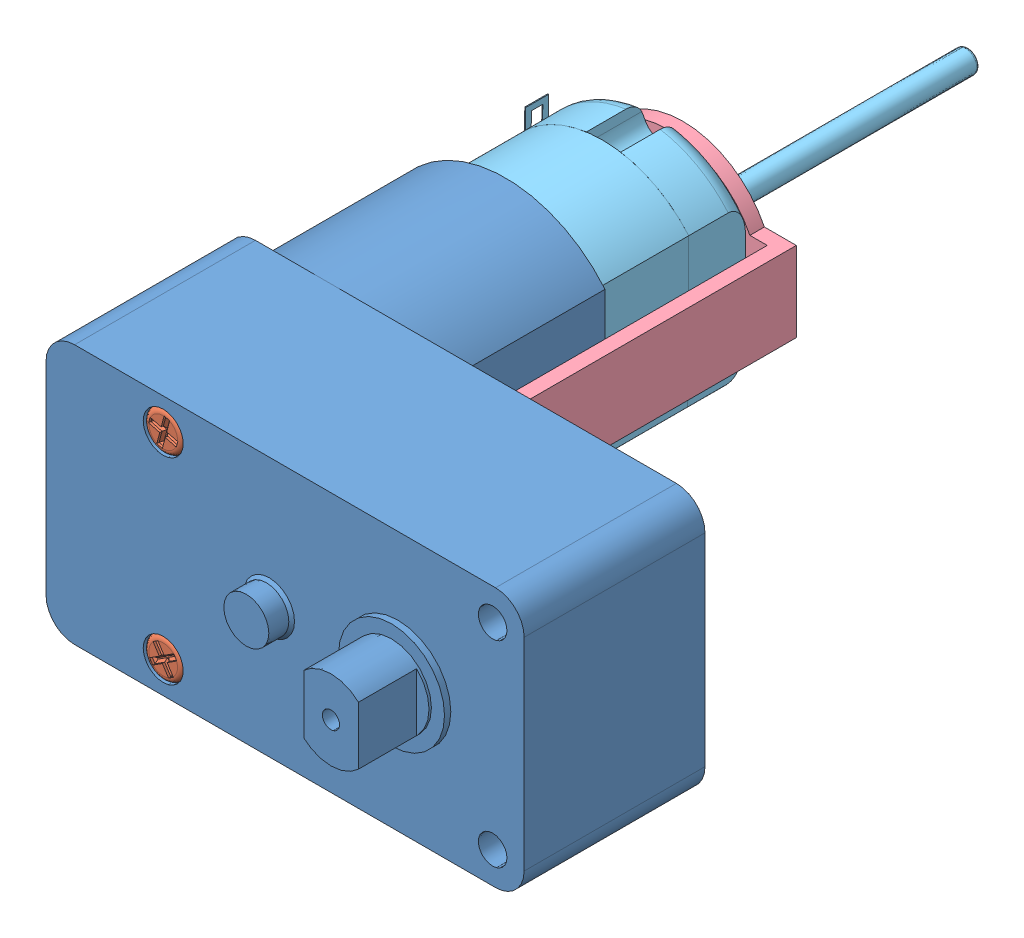
SolidWorks assembly Solarbotics-GM8_Assem, configuration Default. Lengths in mm.
Overall size (48.23 22.7 75.51).
7 component instances, 5 part files, 14 mates.
Components (placement in the parent):
- gm8-2: gm8 [Default] at origin size (47.26 22.7 37.31)
- screw_head1-3: screw_head1 [Default] at (10.2482 19.95 14.2875) x (0.967029 -0.254667 0) z (0 0 1) size (3.5 3.5 1.53)
- screw_head1-4: screw_head1 [Default] at (10.2482 2.75 14.2875) x (0.84007 0.542478 0) z (0 0 1) size (3.5 3.5 1.53)
- screw_head2-3: screw_head2 [Default] at (20.575 11.35 -7.6154) x (-0.966595 0.256308 0) z (0 0 -1) size (3.5 3.5 1.68)
- screw_head2-4: screw_head2 [Default] at (-3.8852 11.35 -7.6154) x (-0.959652 -0.28119 0) z (0 0 -1) size (3.5 3.5 1.68)
- GMstrap1-2: GMstrap1 [Default] at (-1.3452 14.8425 -31.115) size (31.06 15.88 26.04)
- RM3-regular motor-2: RM3-regular motor [Default] at (8.7001 11.4087 -24.13) x (-0.010002 -0.99995 0) z (0 0 -1) size (19.88 16.59 58.73)
Mates (geometry in assembly coordinates):
- Coincident1: coincident aligned: plane of gm8-2 through (39.3 20.2 15.8115) normal (0 0 1); plane of screw_head1-3 through (10.2482 19.95 15.8115) normal (0 0 1)
- Concentric1: concentric anti-aligned: cylinder of gm8-2 through (10.2482 19.95 14.2865) axis (0 0 1) radius 1.75; cylinder of screw_head1-3 through (10.2482 19.95 15.8115) axis (0 0 -1) radius 1.75
- Coincident2: coincident aligned: plane of gm8-2 through (39.3 20.2 15.8115) normal (0 0 1); plane of screw_head1-4 through (10.2482 2.75 15.8115) normal (0 0 1)
- Concentric2: concentric anti-aligned: cylinder of gm8-2 through (10.2482 2.75 14.2865) axis (0 0 1) radius 1.75; cylinder of screw_head1-4 through (10.2482 2.75 15.8115) axis (0 0 -1) radius 1.75
- Coincident3: coincident anti-aligned: plane of gm8-2 through (8.7 11.4847 -4.445) normal (0 0 -1); plane of RM3-regular motor-2 through (8.7 11.398 -4.445) normal (0 0 1)
- Concentric3: concentric anti-aligned: cylinder of gm8-2 through (8.7 11.398 -15.66) axis (0 0 1) radius 10.152; cylinder of RM3-regular motor-2 through (8.7 11.398 -4.445) axis (0 0 -1) radius 9.937
- Coincident4: coincident: plane of gm8-2 through (16.25 11.398 -15.66) normal (-1 0 0); line of RM3-regular motor-2 through (16.25 17.8588 -5.945) axis (0 0 -1)
- Coincident5: coincident anti-aligned: plane of gm8-2 through (20.575 11.35 -5.08) normal (0 0 -1); plane of GMstrap1-2 through (18.67 7.8575 -5.08) normal (0 0 1)
- Concentric11: concentric aligned: circle of gm8-2; circle of GMstrap1-2
- Coincident10: coincident anti-aligned: plane of gm8-2 through (17.4 18.6122 -15.66) normal (1 0 0); plane of GMstrap1-2 through (17.4 14.8425 -5.08) normal (-1 0 0)
- Coincident6: coincident anti-aligned: plane of screw_head2-3 through (20.575 11.35 -7.6154) normal (0 0 1); plane of GMstrap1-2 through (24.639 14.8425 -7.6154) normal (0 0 -1)
- Concentric8: concentric aligned: circle of screw_head2-3; circle of GMstrap1-2
- Coincident11: coincident anti-aligned: plane of screw_head2-4 through (-3.8852 11.35 -7.6154) normal (0 0 1); plane of GMstrap1-2 through (-6.4252 14.8425 -7.6154) normal (0 0 -1)
- Concentric14: concentric aligned: circle of screw_head2-4; circle of GMstrap1-2
